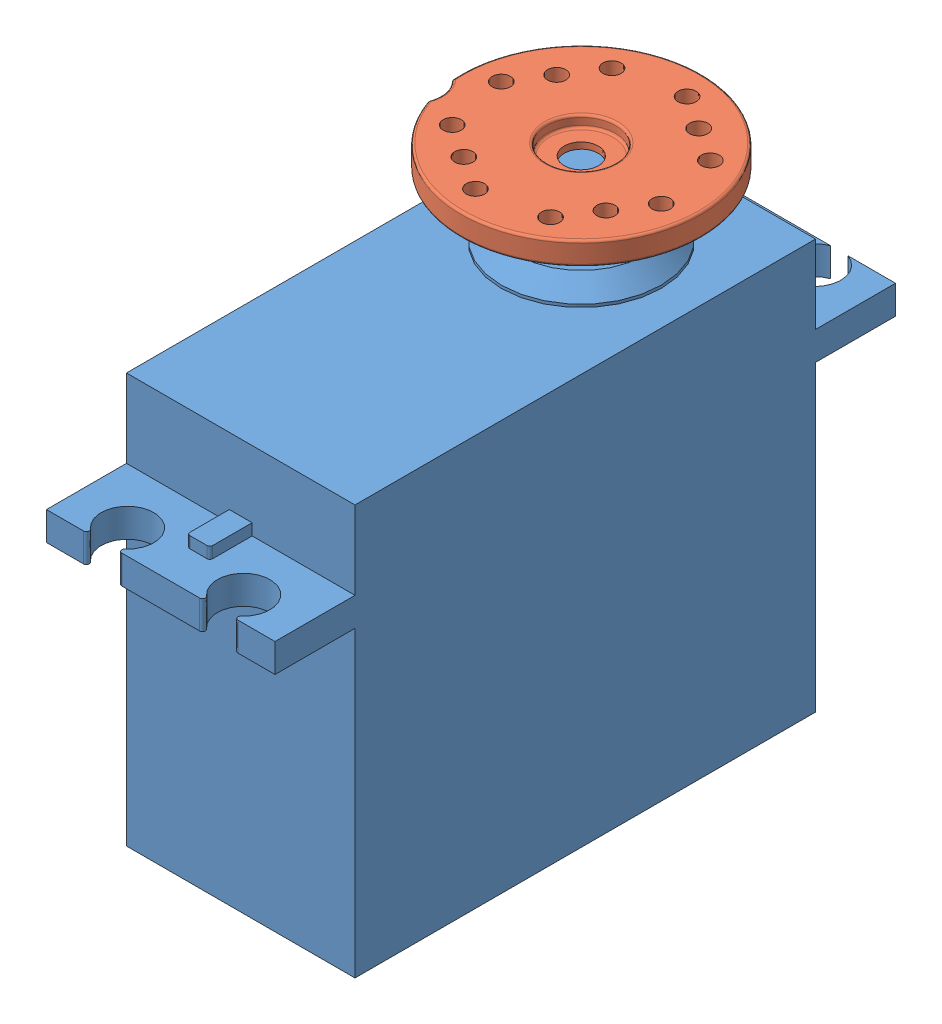
SolidWorks assembly ServoAssembly, configuration Default. Lengths in mm.
Overall size (29.07 43.4 54.3).
2 component instances, 2 part files, 2 mates.
Components (placement in the parent):
- S3151-1: S3151 [Default] at (23.1293 24.5802 33.4889) size (20 41.85 54.3)
- servohorn-1: servohorn [Default] at (23.1293 50.0552 23.8389) x (-0.837169 0 -0.546944) z (-0.546944 0 0.837169) size (21 5.8 21)
Mates (geometry in assembly coordinates):
- Concentric1: concentric aligned: cylinder of S3151-1 through (23.1293 48.5052 23.8389) axis (0 -1 0) radius 3; cylinder of servohorn-1 through (23.1293 47.7552 23.8389) axis (0 -1 0) radius 2.975
- Coincident1: coincident anti-aligned: plane of S3151-1 through (23.1293 44.2552 23.8389) normal (0 1 0); plane of servohorn-1 through (23.1293 44.2552 23.8389) normal (0 -1 0)
